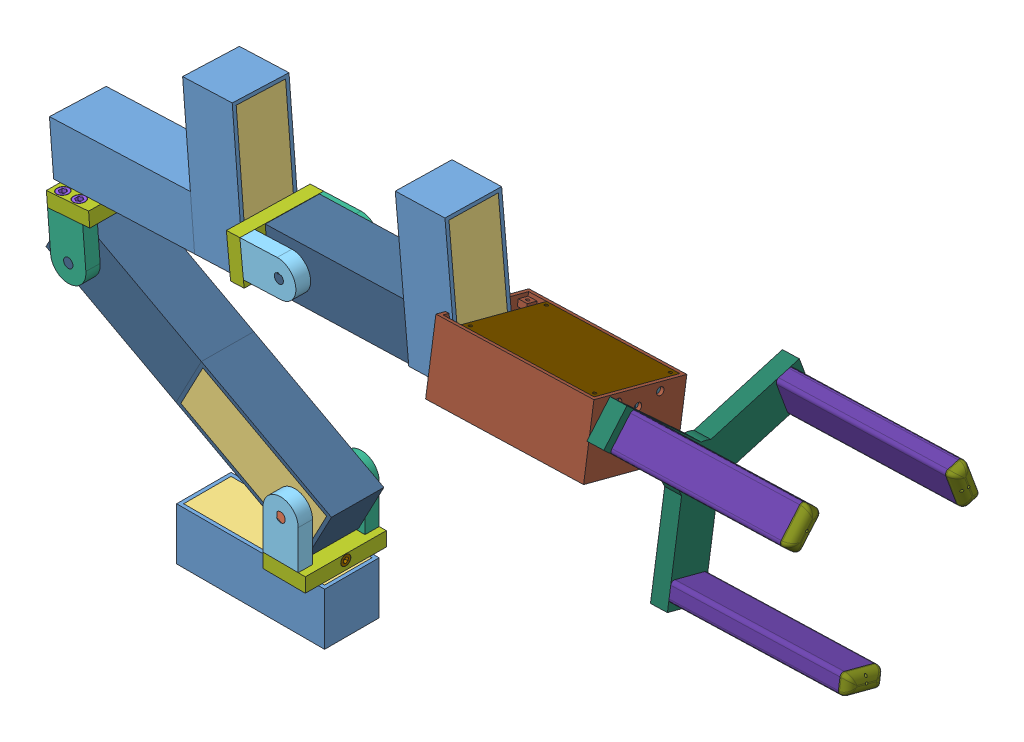
SolidWorks assembly 7DOFArm, configuration Default. Lengths in mm.
Overall size (729.1 390.69 214.42).
106 component instances, 18 part files, 15 mates.
Components (placement in the parent):
- BaseLink-1: BaseLink [Default] at origin size (125 56 46)
  - Motor1WithCase-1: Motor1WithCase [Default] at origin size (125 56 46)
    - ArmBase-1: ArmBase [Default] at origin size (125 44 46)
    - WormGearMotor-2: WormGearMotor [Default] at (-57.7 19.5 0) x (0 0 -1) z (0 -1 0) size (40 117.2 52)
    - ArmBaseCover-2: ArmBaseCover [Default] at (0 44 0) x (-1 0 0) z (0 0 1) size (119 4.5 40)
  - SB608ZZ-1: SB608ZZ [Default] at (39.5 48 0) x (0 -1 0) z (0 0 1) size (7 22 22)
- Link2-1: Link2 [Default] at (39.5 49.0777 0) x (0.99998 0 0.006325) z (-0.006325 0 0.99998) size (36 60 68.86)
  - ConnectingJoint-1: ConnectingJoint [Default] at (-13.0484 0 -9.0061) size (36 60 68.86)
    - BearingJoints-1: BearingJoints [Default] at (10.0484 39.9223 31.0061) size (30 48 12)
    - BearingJoints2-1: BearingJoints2 [Default] at (10.0484 39.9223 -12.9939) x (-1 0 0) z (0 0 -1) size (30 48 12)
    - JointBottom-1: JointBottom [Default] at (13.0484 -5.0777 9.0061) x (0 0 -1) z (1 0 0) size (68 12 36)
    - socket head cap screw_iso-1: socket head cap screw_iso [ISO 4762 M6 x 20 - 20S] at (3.0484 -5.0777 -18.9939) x (0 1 0) z (-0.488199 0 0.872732) size (26 10 10)
    - socket head cap screw_iso-2: socket head cap screw_iso [ISO 4762 M6 x 20 - 20S] at (3.0484 -5.0777 37.0061) x (0 1 0) z (0 0 1) size (26 10 10)
    - socket head cap screw_iso-3: socket head cap screw_iso [ISO 4762 M6 x 20 - 20S] at (17.0484 -5.0777 37.0061) x (0 1 0) z (0 0 1) size (26 10 10)
    - socket head cap screw_iso-4: socket head cap screw_iso [ISO 4762 M6 x 20 - 20S] at (17.0484 -5.0777 -18.9939) x (0 1 0) z (-0.513591 0 0.858035) size (26 10 10)
    - M5X10-1: M5X10 [Default] at (22.2578 2.0842 9.2195) x (-1 0 0) z (0 -0.924225 -0.381849) size (15 8.5 8.5)
- Link3-1: Link3 [Default] at (1.7066 107.4367 -22.2395) x (0.88437 -0.466752 0.005594) z (-0.466743 -0.884388 -0.002952) size (250 68 46)
  - Case2WithBearings-2: Case2WithBearings [Default] at origin size (125 68 46)
    - Motor2WithCase-1: Motor2WithCase [Default] at origin size (125 68 46) (flexible)
      - ArmBase2-1: ArmBase2 [Default] at origin size (125 56 46)
      - WormGearMotor-3: WormGearMotor [Default] at (-57.7 19.5 0) x (0 0 -1) z (0 -1 0) size (40 117.2 52)
      - ArmBaseCover-3: ArmBaseCover [Default] at (0 44 0) x (-1 0 0) z (0 0 1) size (119 4.5 40)
    - SB608ZZ-1: SB608ZZ [Default] at (39.5 48 0) x (0 -1 0) z (0.818908 0 -0.573924) size (7 22 22)
    - SB608ZZ-2: SB608ZZ [Default] at (39.5 3 0) x (0 -1 0) z (0 0 1) size (7 22 22)
  - Case2WithBearings-3: Case2WithBearings [Default] at (-125 44 0) x (-1 0 0) z (0 0 1) size (125 68 46)
    - Motor2WithCase-1: Motor2WithCase [Default] at origin size (125 68 46) (flexible)
      - ArmBase2-1: ArmBase2 [Default] at origin size (125 56 46)
      - WormGearMotor-3: WormGearMotor [Default] at (-57.7 19.5 0) x (0 0 -1) z (0 -1 0) size (40 117.2 52)
      - ArmBaseCover-3: ArmBaseCover [Default] at (0 44 0) x (-1 0 0) z (0 0 1) size (119 4.5 40)
    - SB608ZZ-1: SB608ZZ [Default] at (39.5 48 0) x (0 -1 0) z (0.818908 0 -0.573924) size (7 22 22)
    - SB608ZZ-2: SB608ZZ [Default] at (39.5 3 0) x (0 -1 0) z (0 0 1) size (7 22 22)
- Link6-1: Link6 [Default] at (-144.1753 224.2515 -1.1619) x (0.996653 0.081505 0.006304) z (0.006325 0 -0.99998) size (36 60 68.86)
  - ConnectingJoint-1: ConnectingJoint [Default] at (-13.0484 0 -9.0061) size (36 60 68.86)
    - BearingJoints-1: BearingJoints [Default] at (10.0484 39.9223 31.0061) size (30 48 12)
    - BearingJoints2-1: BearingJoints2 [Default] at (10.0484 39.9223 -12.9939) x (-1 0 0) z (0 0 -1) size (30 48 12)
    - JointBottom-1: JointBottom [Default] at (13.0484 -5.0777 9.0061) x (0 0 -1) z (1 0 0) size (68 12 36)
    - socket head cap screw_iso-1: socket head cap screw_iso [ISO 4762 M6 x 20 - 20S] at (3.0484 -5.0777 -18.9939) x (0 1 0) z (-0.488199 0 0.872732) size (26 10 10)
    - socket head cap screw_iso-2: socket head cap screw_iso [ISO 4762 M6 x 20 - 20S] at (3.0484 -5.0777 37.0061) x (0 1 0) z (0 0 1) size (26 10 10)
    - socket head cap screw_iso-3: socket head cap screw_iso [ISO 4762 M6 x 20 - 20S] at (17.0484 -5.0777 37.0061) x (0 1 0) z (0 0 1) size (26 10 10)
    - socket head cap screw_iso-4: socket head cap screw_iso [ISO 4762 M6 x 20 - 20S] at (17.0484 -5.0777 -18.9939) x (0 1 0) z (-0.513591 0 0.858035) size (26 10 10)
    - M5X10-1: M5X10 [Default] at (22.2578 2.0842 9.2195) x (-1 0 0) z (0 -0.924225 -0.381849) size (15 8.5 8.5)
- Link5-1: Link5 [Default] at (-115.8963 269.5864 11.276) x (-0.995722 -0.081448 -0.043631) z (-0.043528 -0.003043 0.999048) size (181 137 46)
  - Case1WithBearings-1: Case1WithBearings [Default] at origin size (125 56 46)
    - Motor1WithCase-1: Motor1WithCase [Default] at (-7.1067 -6.2049 -11.0572) size (125 56 46)
      - ArmBase-1: ArmBase [Default] at origin size (125 44 46)
      - WormGearMotor-2: WormGearMotor [Default] at (-57.7 19.5 0) x (0 0 -1) z (0 -1 0) size (40 117.2 52)
      - ArmBaseCover-2: ArmBaseCover [Default] at (0 44 0) x (-1 0 0) z (0 0 1) size (119 4.5 40)
    - SB608ZZ-1: SB608ZZ [Default] at (32.3933 41.7951 -11.0572) x (0 -1 0) z (0 0 1) size (7 22 22)
  - Case1WithBearings-2: Case1WithBearings [Default] at (-75.8116 -17.5981 0) x (0 1 0) z (0 0 1) size (125 56 46)
    - Motor1WithCase-1: Motor1WithCase [Default] at (-7.1067 -6.2049 -11.0572) size (125 56 46)
      - ArmBase-1: ArmBase [Default] at origin size (125 44 46)
      - WormGearMotor-2: WormGearMotor [Default] at (-57.7 19.5 0) x (0 0 -1) z (0 -1 0) size (40 117.2 52)
      - ArmBaseCover-2: ArmBaseCover [Default] at (0 44 0) x (-1 0 0) z (0 0 1) size (119 4.5 40)
    - SB608ZZ-1: SB608ZZ [Default] at (32.3933 41.7951 -11.0572) x (0 -1 0) z (0 0 1) size (7 22 22)
- Link6-2: Link6 [Default] at (3.9676 264.5408 5.4154) x (0.082268 -0.996459 -0.017334) z (-0.042065 -0.02085 0.998897) size (36 60 68.86)
  - ConnectingJoint-1: ConnectingJoint [Default] at (-13.0484 0 -9.0061) size (36 60 68.86)
    - BearingJoints-1: BearingJoints [Default] at (10.0484 39.9223 31.0061) size (30 48 12)
    - BearingJoints2-1: BearingJoints2 [Default] at (10.0484 39.9223 -12.9939) x (-1 0 0) z (0 0 -1) size (30 48 12)
    - JointBottom-1: JointBottom [Default] at (13.0484 -5.0777 9.0061) x (0 0 -1) z (1 0 0) size (68 12 36)
    - socket head cap screw_iso-1: socket head cap screw_iso [ISO 4762 M6 x 20 - 20S] at (3.0484 -5.0777 -18.9939) x (0 1 0) z (-0.488199 0 0.872732) size (26 10 10)
    - socket head cap screw_iso-2: socket head cap screw_iso [ISO 4762 M6 x 20 - 20S] at (3.0484 -5.0777 37.0061) x (0 1 0) z (0 0 1) size (26 10 10)
    - socket head cap screw_iso-3: socket head cap screw_iso [ISO 4762 M6 x 20 - 20S] at (17.0484 -5.0777 37.0061) x (0 1 0) z (0 0 1) size (26 10 10)
    - socket head cap screw_iso-4: socket head cap screw_iso [ISO 4762 M6 x 20 - 20S] at (17.0484 -5.0777 -18.9939) x (0 1 0) z (-0.513591 0 0.858035) size (26 10 10)
    - M5X10-1: M5X10 [Default] at (22.2578 2.0842 9.2195) x (-1 0 0) z (0 -0.924225 -0.381849) size (15 8.5 8.5)
- Link7-1: Link7 [Default] at (81.9049 273.1948 30.9024) x (-0.996406 -0.072702 -0.043478) z (0.073528 -0.997136 -0.017717) size (181 68 125)
  - Case2WithBearings-2: Case2WithBearings [Default] at origin size (125 68 46)
    - Motor2WithCase-1: Motor2WithCase [Default] at origin size (125 68 46) (flexible)
      - ArmBase2-1: ArmBase2 [Default] at origin size (125 56 46)
      - WormGearMotor-3: WormGearMotor [Default] at (-57.7 19.5 0) x (0 0 -1) z (0 -1 0) size (40 117.2 52)
      - ArmBaseCover-3: ArmBaseCover [Default] at (0 44 0) x (-1 0 0) z (0 0 1) size (119 4.5 40)
    - SB608ZZ-1: SB608ZZ [Default] at (39.5 48 0) x (0 -1 0) z (0.818908 0 -0.573924) size (7 22 22)
    - SB608ZZ-2: SB608ZZ [Default] at (39.5 3 0) x (0 -1 0) z (0 0 1) size (7 22 22)
  - Case1WithBearings-1: Case1WithBearings [Default] at (-68.7049 9.9428 -32.3933) x (0 0 1) z (0 -1 0) size (125 56 46)
    - Motor1WithCase-1: Motor1WithCase [Default] at (-7.1067 -6.2049 -11.0572) size (125 56 46)
      - ArmBase-1: ArmBase [Default] at origin size (125 44 46)
      - WormGearMotor-2: WormGearMotor [Default] at (-57.7 19.5 0) x (0 0 -1) z (0 -1 0) size (40 117.2 52)
      - ArmBaseCover-2: ArmBaseCover [Default] at (0 44 0) x (-1 0 0) z (0 0 1) size (119 4.5 40)
    - SB608ZZ-1: SB608ZZ [Default] at (32.3933 41.7951 -11.0572) x (0 -1 0) z (0 0 1) size (7 22 22)
- EndEffector-1: EndEffector [Default] at (178.2144 276.3143 15.0306) x (-0.058185 0.214356 0.975021) z (-0.996406 -0.072702 -0.043478) size (170.88 147.99 358)
  - GrapperWithServos-1: GrapperWithServos [Default] at (-20.6091 -66.5283 -141.4389) size (170.88 147.99 358)
    - ServoHolder-1: ServoHolder [Default] at (20.6091 41.5283 66.4389) size (76 55.75 190)
    - ServoWithHornCover-1: ServoWithHornCover [Default] at (-47.2507 32.9202 51.0729) x (0 0 -1) z (1 0 0) size (60.01 49.75 41.52) (flexible)
      - MG996R-1: MG996R [Default] at (22.884 11.6081 50.6098) size (53.5 42.75 19.5)
      - ServoHornWithGroove-1: ServoHornWithGroove [Default] at (12.384 56.3581 50.6098) x (0.653288 0 0.75711) z (0.75711 0 -0.653288) size (30 9.5 30)
      - ServoCover-1: ServoCover [Default] at (34.0772 41.3581 67.8598) x (-1 0 0) z (0 0 -1) size (57.5 20 34.5)
    - ServoWithHornCover-2: ServoWithHornCover [Default] at (-12.7507 32.9202 51.0729) x (0 0 -1) z (1 0 0) size (60.01 49.75 41.52) (flexible)
      - MG996R-1: MG996R [Default] at (22.884 11.6081 50.6098) size (53.5 42.75 19.5)
      - ServoHornWithGroove-1: ServoHornWithGroove [Default] at (12.384 56.3581 50.6098) x (0.586538 0 0.809922) z (0.809922 0 -0.586538) size (30 9.5 30)
      - ServoCover-1: ServoCover [Default] at (34.0772 41.3581 67.8598) x (-1 0 0) z (0 0 -1) size (57.5 20 34.5)
    - 3GripperAssembly-1: 3GripperAssembly [Default] at (-30.3334 -49.3942 11.9719) x (1 0 0) z (0 1 0) size (170.88 173 147.99)
      - EndEffector3Grapper-1: EndEffector3Grapper [Default] at (50.9425 60.533 115.9226) size (170.88 20 147.99)
      - FingerAssembly-1: FingerAssembly [Default] at (105.0348 198.5242 138.6511) x (-0.5 0 0.866025) z (0 1 0) size (30 15 158)
        - FingerTip-1: FingerTip [Default] at (7.3627 17.1904 24.0088) size (30 15 11)
        - Finger-1: Finger [Default] at (7.3627 18.2904 -122.9912) x (1 0 0) z (0 -1 0) size (30 150 15)
      - FingerAssembly-2: FingerAssembly [Default] at (4.2129 198.5242 151.4036) x (-0.5 0 -0.866025) z (0 1 0) size (30 15 158)
        - FingerTip-1: FingerTip [Default] at (7.3627 17.1904 24.0088) size (30 15 11)
        - Finger-1: Finger [Default] at (7.3627 18.2904 -122.9912) x (1 0 0) z (0 -1 0) size (30 150 15)
      - FingerAssembly-3: FingerAssembly [Default] at (43.5799 198.5242 57.713) x (1 0 0) z (0 1 0) size (30 15 158)
        - FingerTip-1: FingerTip [Default] at (7.3627 17.1904 24.0088) size (30 15 11)
        - Finger-1: Finger [Default] at (7.3627 18.2904 -122.9912) x (1 0 0) z (0 -1 0) size (30 150 15)
    - ServoWithHornCover-4: ServoWithHornCover [Default] at (-30.0007 32.9202 111.5729) x (0 0 -1) z (1 0 0) size (60.01 49.75 41.52)
      - MG996R-1: MG996R [Default] at (22.884 11.6081 50.6098) size (53.5 42.75 19.5)
      - ServoHornWithGroove-1: ServoHornWithGroove [Default] at (12.384 56.3581 50.6098) x (-0.837169 0 -0.546944) z (-0.546944 0 0.837169) size (30 9.5 30)
      - ServoCover-1: ServoCover [Default] at (34.0772 41.3581 67.8598) x (-1 0 0) z (0 0 -1) size (57.5 20 34.5)
    - ServoHolderCover-1: ServoHolderCover [Default] at (20.6091 94.2783 58.4389) x (0 0 -1) z (1 0 0) size (118 3 70)
    - socket head cap screw_iso-1: socket head cap screw_iso [ISO 4762 M6 x 20 - 20S] at (20.6091 66.5283 -63.5611) x (0 0 1) z (-0.923728 -0.383049 0) size (26 10 10)
Mates (geometry in assembly coordinates):
- Coincident1: coordinate: unknown of BaseLink-1
- Concentric1: concentric aligned: cylinder of BaseLink-1/SB608ZZ-1 through (39.5 41.3 0) axis (0 -1 0) radius 11; cylinder of Link2-1/ConnectingJoint-1/JointBottom-1 through (39.5 48 0) axis (0 -1 0) radius 11
- Coincident2: coincident anti-aligned: plane of BaseLink-1/SB608ZZ-1 through (50.2 48 0) normal (0 1 0); plane of Link2-1/ConnectingJoint-1/JointBottom-1 through (39.5 48 0) normal (0 -1 0)
- Concentric2: concentric anti-aligned: cylinder of Link2-1/ConnectingJoint-1/BearingJoints-1 through (36.285 89 33.9803) axis (0.006325 0 -0.99998) radius 4; cylinder of Link3-1/Case2WithBearings-2/Motor2WithCase-1/WormGearMotor-3 through (36.4115 89 13.9807) axis (-0.006325 0 0.99998) radius 4
- Coincident3: coincident anti-aligned: plane of Link2-1/ConnectingJoint-1/BearingJoints-1 through (36.3356 89 25.9805) normal (0.006325 0 -0.99998); plane of Link3-1/Case2WithBearings-2/SB608ZZ-1 through (34.9944 99.6156 25.972) normal (-0.006325 0 0.99998)
- Concentric3: concentric anti-aligned: cylinder of Link3-1/Case2WithBearings-3/SB608ZZ-2 through (-144.0741 184.2175 24.5393) axis (-0.006325 0 0.99998) radius 11; cylinder of Link4-1/ConnectingJoint-1/BearingJoints2-1 through (-144.076 184.2175 24.8393) axis (0.006325 0 -0.99998) radius 11
- Coincident4: coincident anti-aligned: plane of Link3-1/Case2WithBearings-3/SB608ZZ-1 through (-134.2264 189.1005 -27.0994) normal (0.006325 0 -0.99998); plane of Link4-1/ConnectingJoint-1/BearingJoints-1 through (-143.747 184.2175 -27.1597) normal (-0.006325 0 0.99998)
- Concentric4: concentric aligned: cylinder of Link4-1/ConnectingJoint-1/JointBottom-1 through (-144.2632 225.3256 -1.1624) axis (-0.081504 0.996673 -0.000516) radius 11; cylinder of Link5-1/Case1WithBearings-1/SB608ZZ-1 through (-144.8093 232.0033 -1.1659) axis (-0.081504 0.996673 -0.000516) radius 11
- Coincident5: coincident anti-aligned: plane of Link4-1/ConnectingJoint-1/JointBottom-1 through (-144.2632 225.3256 -1.1624) normal (-0.081504 0.996673 -0.000516); plane of Link5-1/Case1WithBearings-1/SB608ZZ-1 through (-154.9174 224.4541 -1.6293) normal (0.081504 -0.996673 0.000516)
- Concentric5: concentric aligned: cylinder of Link5-1/Case1WithBearings-2/SB608ZZ-1 through (-3.7768 263.9073 5.0761) axis (-0.995722 -0.081448 -0.043631) radius 11; cylinder of Link6-2/ConnectingJoint-1/JointBottom-1 through (2.8945 264.453 5.3684) axis (-0.995722 -0.081448 -0.043631) radius 11
- Coincident6: coincident anti-aligned: plane of Link5-1/Case1WithBearings-2/SB608ZZ-1 through (3.7666 253.7886 5.3739) normal (0.995722 0.081448 0.043631); plane of Link6-2/ConnectingJoint-1/JointBottom-1 through (2.8945 264.453 5.3684) normal (-0.995722 -0.081448 -0.043631)
- Concentric6: concentric aligned: cylinder of Link6-2/ConnectingJoint-1/BearingJoints2-1 through (44.566 271.3239 -18.762) axis (-0.042065 -0.02085 0.998897) radius 11; cylinder of Link7-1/Case2WithBearings-2/SB608ZZ-1 through (44.2842 271.1842 -12.0694) axis (-0.042065 -0.02085 0.998897) radius 11
- Coincident7: coincident anti-aligned: plane of Link6-2/ConnectingJoint-1/BearingJoints-1 through (42.3786 270.2397 33.1806) normal (0.042065 0.02085 -0.998897); plane of Link7-1/Case2WithBearings-2/SB608ZZ-2 through (32.7633 269.5381 32.7611) normal (-0.042065 -0.02085 0.998897)
- Concentric7: concentric aligned: cylinder of Link7-1/Case1WithBearings-1/SB608ZZ-1 through (186.2152 281.1792 14.4385) axis (-0.996406 -0.072702 -0.043478) radius 11; circle of EndEffector-1/GrapperWithServos-1/ServoHolder-1
- Coincident8: coincident aligned: plane of Link7-1/Case1WithBearings-1/SB608ZZ-1 through (193.6779 270.9969 14.5403) normal (0.996406 0.072702 0.043478); circle of EndEffector-1/GrapperWithServos-1/ServoHolder-1
